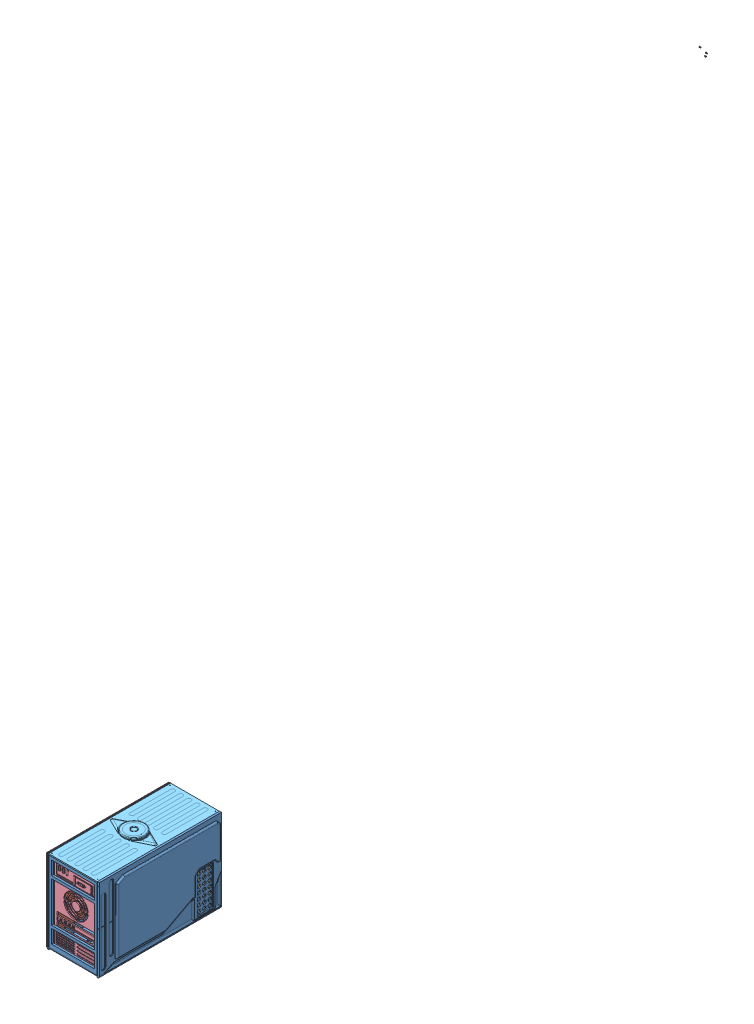
SolidWorks assembly CPU_ASSEMBLY, configuration Default. Lengths in mm.
Overall size (1406.49 5598.82 4837.83).
8 component instances, 6 part files, 11 mates.
Components (placement in the parent):
- Part2-1: Part2 [Default] at (179.4529 612.5583 996.8708) size (514.35 819.34 1143.17)
- Right_panel-1: Right_panel [Default] at (171.8329 614.5107 996.8708) x (0 0 1) z (0 -1 0) size (1143 11.43 757.68)
- Front_panel-6: Front_panel [Default] at (636.6529 612.5583 1015.9208) x (-1 0 0) z (0 0 -1) size (453.39 748.79 30.48)
- backside-3: backside [Default] at (181.3579 603.0333 2120.8208) size (453.39 758.19 19.1)
- Top_panel-5: Top_panel [Default] at (179.4529 1361.2233 2139.8708) size (457.2 41.83 1143)
- countersunk bolt_ai-3: countersunk bolt_ai [CSBOLT 0.2500-20x0.4375x0.4375-S-N] at (1443.4482 6131.9956 -2691.6927) size (11.11 12.32 12.19)
- countersunk bolt_ai-4: countersunk bolt_ai [CSBOLT 0.2500-20x0.4375x0.4375-S-N] at (1566.8954 6146.0543 -2628.341) x (-1 0 0) z (0 -0.924225 -0.381849) size (11.11 12.32 12.19)
- countersunk bolt_ai-5: countersunk bolt_ai [CSBOLT 0.2500-20x0.4375x0.4375-S-N] at (1526.7326 6136.2597 -2668.6769) size (11.11 12.32 12.19)
Mates (geometry in assembly coordinates):
- Coincident10: coincident aligned: line of Part2-1 through (171.8329 614.4633 2139.8708) axis (0 1 0); line of Right_panel-1 through (171.8329 614.5107 2139.8708) axis (0 1 0)
- Coincident11: coincident anti-aligned: plane of Part2-1 through (674.7539 690.6633 2063.6708) normal (0 1 0); plane of Right_panel-1 through (160.4029 690.6633 1073.0234) normal (0 -1 0)
- Parallel3: parallel anti-aligned: plane of Part2-1 through (171.8329 614.4633 996.8708) normal (0 0.707107 -0.707107); plane of Right_panel-1 through (160.4029 614.5107 996.8708) normal (0 -0.707107 0.707107)
- Coincident63: coincident anti-aligned: plane of Part2-1 through (179.4529 612.5583 2139.8708) normal (0 1 0); plane of Front_panel-6 through (636.6529 612.5583 996.8708) normal (0 -1 0)
- Coincident65: coincident aligned: line of Part2-1 through (636.6529 1361.3503 1015.9208) axis (0 -1 0); line of Front_panel-6 through (636.6529 1361.3503 1015.9208) axis (0 -1 0)
- Parallel10: parallel anti-aligned: plane of Part2-1 through (179.4529 1374.5583 2139.8708) normal (1 0 0); plane of Front_panel-6 through (183.2629 1361.3503 996.8708) normal (-1 0 0)
- Coincident70: coincident aligned: line of Part2-1 through (634.7479 1361.2233 2120.8208) axis (-1 0 0); line of backside-3 through (634.7479 1361.2233 2120.8208) axis (-1 0 0)
- Coincident74: coincident aligned: line of Part2-1 through (634.7479 614.4633 2120.8208) axis (0 1 0); line of backside-3 through (634.7479 603.0333 2120.8208) axis (0 1 0)
- Coincident75: coincident aligned: line of Part2-1 through (181.3579 1361.2233 2139.8708) axis (1 0 0); line of Top_panel-5 through (179.4529 1361.2233 2139.8708) axis (1 0 0)
- Parallel14: parallel aligned: line of Part2-1 through (636.6529 1374.5583 2139.8708) axis (0 0 -1); line of Top_panel-5 through (636.6529 1372.6533 2139.8708) axis (0 0 -1)
- Coincident79: coincident anti-aligned: plane of Part2-1 through (636.6529 1374.5583 2139.8708) normal (-1 0 0); plane of Top_panel-5 through (636.6529 1372.6533 2139.8708) normal (1 0 0)
